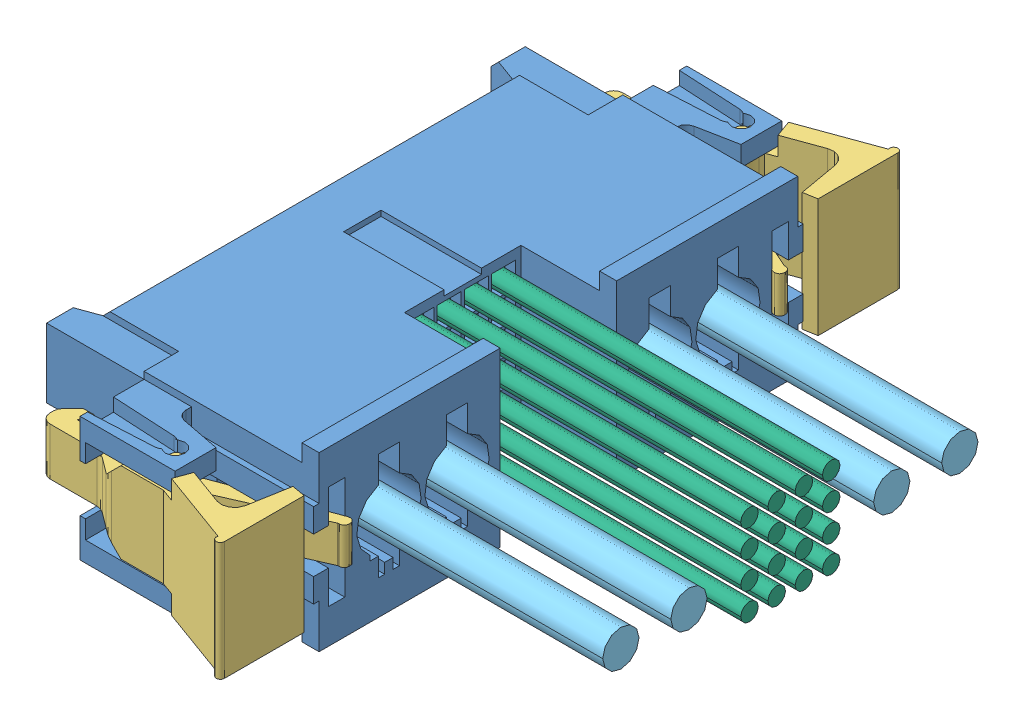
SolidWorks assembly MPCC_2_16_2_L_46_80_00_S, configuration Default. Lengths in mm.
Overall size (37.93 12.66 50.05).
13 component instances, 6 part files, 0 mates.
Components (placement in the parent):
- _MPC_2_16_2_C_body_2-1: _MPC_2_16_2_C_body_2 [Default] at (0 -6.33 0) x (0 0 1) z (-1 0 0) size (44.55 12.66 20.9)
- _MPC_16__V_signal_pins_4-1: _MPC_16__V_signal_pins_4 [Default] at (-16.28 0 0) x (0 0 1) z (-1 0 0) size (7.32 6.5 10.38)
- _LTC_22_6-1: _LTC_22_6 [Default] at (-7.3 0 20.775) x (0 -1 0) z (0 0 -1) size (8.7 17.64 9.44)
- _LTC_22_6-2: _LTC_22_6 [Default] at (-7.3 0 -20.775) x (0 1 0) z (0 0 1) size (8.7 17.64 9.44)
- _MPC_01_V_pp_9-1: _MPC_01_V_pp_9 [Default] at (-15.85 -2.54 -12.445) x (-1 0 0) z (0 0 -1) size (9.41 7.05 3)
- _MPC_01_V_pp_9-2: _MPC_01_V_pp_9 [Default] at (-15.85 -2.54 -7.445) x (-1 0 0) z (0 0 -1) size (9.41 7.05 3)
- _MPC_01_V_pp_9-3: _MPC_01_V_pp_9 [Default] at (-15.85 -2.54 7.445) x (-1 0 0) z (0 0 -1) size (9.41 7.05 3)
- _MPC_01_V_pp_9-4: _MPC_01_V_pp_9 [Default] at (-15.85 -2.54 12.445) x (-1 0 0) z (0 0 -1) size (9.41 7.05 3)
- _DWC_14_1_14-1: _DWC_14_1_14 [Default] at (-7.97 -0.15 12.445) x (0 0 1) z (-1 0 0) size (2.67 2.67 25)
- _DWC_14_1_14-2: _DWC_14_1_14 [Default] at (-7.97 -0.15 7.445) x (0 0 1) z (-1 0 0) size (2.67 2.67 25)
- _DWC_14_1_14-3: _DWC_14_1_14 [Default] at (-7.97 -0.15 -7.445) x (0 0 1) z (-1 0 0) size (2.67 2.67 25)
- _DWC_14_1_14-4: _DWC_14_1_14 [Default] at (-7.97 -0.15 -12.445) x (0 0 1) z (-1 0 0) size (2.67 2.67 25)
- _DWC_26_16_19-1: _DWC_26_16_19 [Default] at (-8.97 -2.555 0) x (0 0 1) z (-1 0 0) size (8 8 26)
